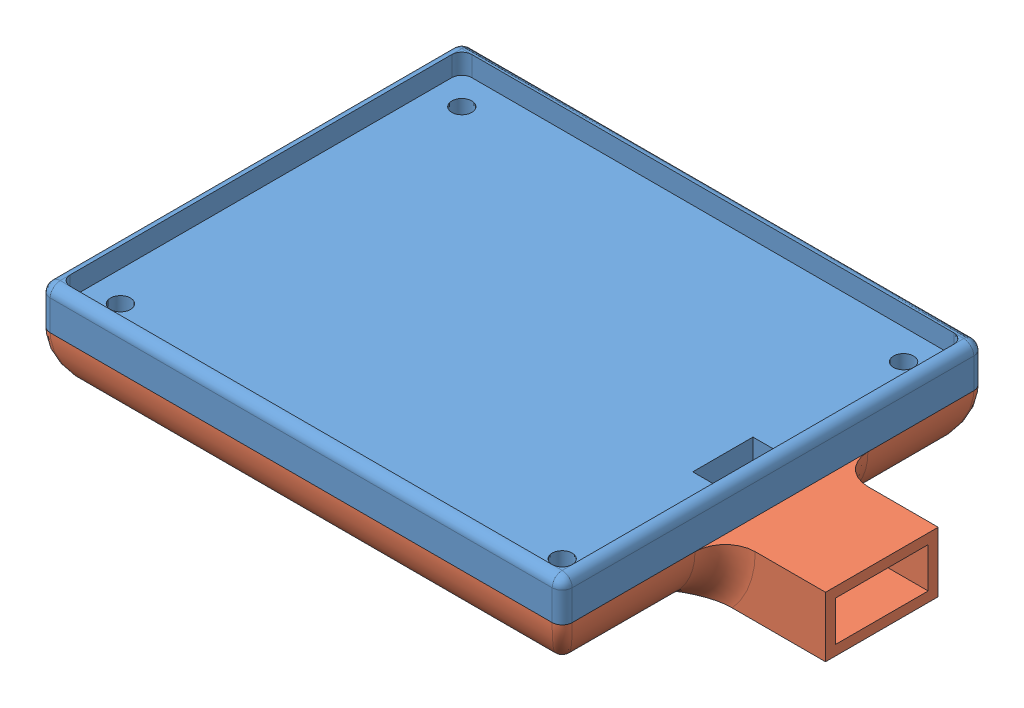
SolidWorks assembly Сборка3, configuration По умолчанию. Lengths in mm.
Overall size (62 10 42).
2 component instances, 2 part files, 2 mates.
Components (placement in the parent):
- Деталь1-1: Деталь1 [По умолчанию] at origin size (52 4 42)
- 2-1: 2 [По умолчанию] at (-2.3321 -6 -0.5816) size (62 6 42)
Mates (geometry in assembly coordinates):
- Совпадение1: coincident: line of Деталь1-1 through (-26 0 -20) axis (0 0 1); line of 2-1 through (-26 0 -20) axis (0 0 1)
- Совпадение2: coincident: circle of Деталь1-1; circle of 2-1
